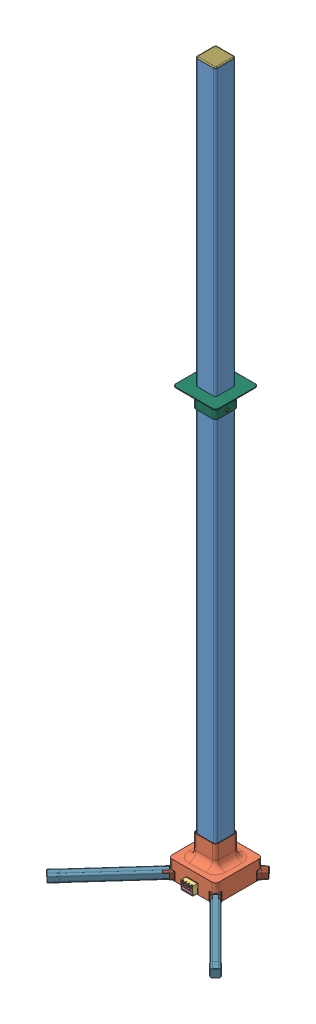
SolidWorks assembly GameOfLightLamp_V3, configuration Default. Lengths in mm.
Overall size (307.74 1257.8 307.74).
87 component instances, 35 part files, 55 mates.
Components (placement in the parent):
- Tube-1: Tube [Default] at origin size (35.56 1219.2 35.56)
- BottomCap^GameOfLightLamp_V3-1: BottomCap^GameOfLightLamp_V3 [Default] x (1 0 0) z (0 1 0) size (86.56 86.56 73.03) (virtual)
- MainBoard-1: MainBoard [Default] at (0 -14.3 0) size (70.02 38.08 102.19)
  - MainBoard-1: MainBoard [Default] at origin size (70.02 1.6 70.02)
  - 691311500104-1: 691311500104 [Default] at (1.7397 7.15 -0.127) x (0 0 1) z (0 1 0) size (22.32 8.5 16)
    - 691311500104_01-1: 691311500104_01 [Default] at origin size (1 1 15)
    - 691311500104_02-1: 691311500104_02 [Default] at origin size (1 1 15)
    - 691311500104_03-1: 691311500104_03 [Default] at origin size (1 1 15)
    - 691311500104_04-1: 691311500104_04 [Default] at origin size (1 1 15)
    - 691311500104_05-1: 691311500104_05 [Default] at origin size (22.32 8.5 12)
  - 691351500004-1: 691351500004 [Default] at (1.1147 18.3 -0.127) x (0 0 -1) z (-1 0 0) size (20.42 18.2 15.1)
    - 691351500004_01-1: 691351500004_01 [Default] at origin size (3.9 4.9 7)
    - 691351500004_02-1: 691351500004_02 [Default] at origin size (3.9 4.9 7)
    - 691351500004_03-1: 691351500004_03 [Default] at origin size (3.9 4.9 7)
    - 691351500004_04-1: 691351500004_04 [Default] at origin size (3.9 4.9 7)
    - 691351500004_05-1: 691351500004_05 [Default] at origin size (3.41 13.5 4.75)
    - 691351500004_06-1: 691351500004_06 [Default] at origin size (3.41 13.5 4.75)
    - 691351500004_07-1: 691351500004_07 [Default] at origin size (3.41 13.5 4.75)
    - 691351500004_08-1: 691351500004_08 [Default] at origin size (3.41 13.5 4.75)
    - 691351500004_09-1: 691351500004_09 [Default] at origin size (3.8 3.8 6.92)
    - 691351500004_10-1: 691351500004_10 [Default] at origin size (3.8 3.8 6.92)
    - 691351500004_11-1: 691351500004_11 [Default] at origin size (3.8 3.8 6.92)
    - 691351500004_12-1: 691351500004_12 [Default] at origin size (3.8 3.8 6.92)
    - 691351500004_13-1: 691351500004_13 [Default] at origin size (20.42 18.2 15.1)
    - 691351500004_14-1: 691351500004_14 [Default] at origin size (19.22 3 13.65)
  - 691351500004-2: 691351500004 [Default] at (-0.127 -4.675 -46.6672) x (1 0 0) z (0 -1 0) size (20.42 18.2 15.1)
    - 691351500004_01-1: 691351500004_01 [Default] at origin size (3.9 4.9 7)
    - 691351500004_02-1: 691351500004_02 [Default] at origin size (3.9 4.9 7)
    - 691351500004_03-1: 691351500004_03 [Default] at origin size (3.9 4.9 7)
    - 691351500004_04-1: 691351500004_04 [Default] at origin size (3.9 4.9 7)
    - 691351500004_05-1: 691351500004_05 [Default] at origin size (3.41 13.5 4.75)
    - 691351500004_06-1: 691351500004_06 [Default] at origin size (3.41 13.5 4.75)
    - 691351500004_07-1: 691351500004_07 [Default] at origin size (3.41 13.5 4.75)
    - 691351500004_08-1: 691351500004_08 [Default] at origin size (3.41 13.5 4.75)
    - 691351500004_09-1: 691351500004_09 [Default] at origin size (3.8 3.8 6.92)
    - 691351500004_10-1: 691351500004_10 [Default] at origin size (3.8 3.8 6.92)
    - 691351500004_11-1: 691351500004_11 [Default] at origin size (3.8 3.8 6.92)
    - 691351500004_12-1: 691351500004_12 [Default] at origin size (3.8 3.8 6.92)
    - 691351500004_13-1: 691351500004_13 [Default] at origin size (20.42 18.2 15.1)
    - 691351500004_14-1: 691351500004_14 [Default] at origin size (19.22 3 13.65)
  - 691351500004-3: 691351500004 [Default] at (0.1164 -4.675 46.6248) x (-1 0 0) z (0 -1 0) size (20.42 18.2 15.1)
    - 691351500004_01-1: 691351500004_01 [Default] at origin size (3.9 4.9 7)
    - 691351500004_02-1: 691351500004_02 [Default] at origin size (3.9 4.9 7)
    - 691351500004_03-1: 691351500004_03 [Default] at origin size (3.9 4.9 7)
    - 691351500004_04-1: 691351500004_04 [Default] at origin size (3.9 4.9 7)
    - 691351500004_05-1: 691351500004_05 [Default] at origin size (3.41 13.5 4.75)
    - 691351500004_06-1: 691351500004_06 [Default] at origin size (3.41 13.5 4.75)
    - 691351500004_07-1: 691351500004_07 [Default] at origin size (3.41 13.5 4.75)
    - 691351500004_08-1: 691351500004_08 [Default] at origin size (3.41 13.5 4.75)
    - 691351500004_09-1: 691351500004_09 [Default] at origin size (3.8 3.8 6.92)
    - 691351500004_10-1: 691351500004_10 [Default] at origin size (3.8 3.8 6.92)
    - 691351500004_11-1: 691351500004_11 [Default] at origin size (3.8 3.8 6.92)
    - 691351500004_12-1: 691351500004_12 [Default] at origin size (3.8 3.8 6.92)
    - 691351500004_13-1: 691351500004_13 [Default] at origin size (20.42 18.2 15.1)
    - 691351500004_14-1: 691351500004_14 [Default] at origin size (19.22 3 13.65)
  - 691312510004-1: 691312510004 [Default] at (0.1164 -4.05 35.4748) size (20.32 12 12)
    - 691312510004_01-1: 691312510004_01 [Default] at origin size (1 7.8 9.2)
    - 691312510004_02-1: 691312510004_02 [Default] at origin size (1 7.8 9.2)
    - 691312510004_03-1: 691312510004_03 [Default] at origin size (1 7.8 9.2)
    - 691312510004_04-1: 691312510004_04 [Default] at origin size (1 7.8 9.2)
    - 691312510004_05-1: 691312510004_05 [Default] at origin size (20.32 8.5 12)
  - 691312510004-2: 691312510004 [Default] at (-0.127 -4.05 -35.5172) x (-1 0 0) z (0 0 -1) size (20.32 12 12)
    - 691312510004_01-1: 691312510004_01 [Default] at origin size (1 7.8 9.2)
    - 691312510004_02-1: 691312510004_02 [Default] at origin size (1 7.8 9.2)
    - 691312510004_03-1: 691312510004_03 [Default] at origin size (1 7.8 9.2)
    - 691312510004_04-1: 691312510004_04 [Default] at origin size (1 7.8 9.2)
    - 691312510004_05-1: 691312510004_05 [Default] at origin size (20.32 8.5 12)
  - Part1^MainBoard-1: Part1^MainBoard [Default] at (-15.494 0 0) x (0 0 -1) z (1 0 0) size (8 8 10) (virtual)
- BottomLid^GameOfLightLamp_V3-1: BottomLid^GameOfLightLamp_V3 [Default] at (0 -14.3 0) x (-1 0 0) z (0 -1 0) size (103.15 103.15 17.42) (virtual)
- TopCap^GameOfLightLamp_V3-1: TopCap^GameOfLightLamp_V3 [Default] at (0 1219.2 0) x (1 0 0) z (0 1 0) size (39.28 39.28 21.05) (virtual)
- PVC^GameOfLightLamp_V3-1: PVC^GameOfLightLamp_V3 [Default] at (0 19.05 0) x (1 0 0) z (0 1 0) size (26.67 26.67 1200.15) (virtual)
- LampShade-1: LampShade [10in] at (0 919.2 0) size (254 100 254) (hidden)
- LampShade-2: LampShade [7in] at (0 1019.2 0) size (177.8 100 177.8) (hidden)
- LampShade-3: LampShade [7in] at (0 819.2 0) size (177.8 100 177.8) (hidden)
- LampShade-4: LampShade [4in] at (0 719.2 0) size (101.6 100 101.6) (hidden)
- LampShade-5: LampShade [4in] at (0 1119.2 0) size (101.6 100 101.6) (hidden)
- LegTube-1: LegTube [Default] at (40.5174 -23.9225 -40.5174) x (-0.707107 0 -0.707107) z (-0.025184 -0.999366 0.025184) size (14.48 152.91 14.48) (hidden)
- LegTube-5: LegTube [Default] at (40.5174 -23.9225 40.5174) x (0.707107 0 -0.707107) z (-0.025184 -0.999366 -0.025184) size (14.48 152.91 14.48)
- LegTube-6: LegTube [Default] at (-40.5174 -23.9225 40.5174) x (0.707107 0 0.707107) z (0.025184 -0.999366 -0.025184) size (14.48 152.91 14.48)
- LegTube-7: LegTube [Default] at (-40.5174 -23.9225 -40.5174) x (-0.707107 0 0.707107) z (0.025184 -0.999366 0.025184) size (14.48 152.91 14.48)
- HoldingCap^GameOfLightLamp_V3-1: HoldingCap^GameOfLightLamp_V3 [Default] at (0 719.2 0) x (-1 0 0) z (0 -1 0) size (76.03 76.03 33.75) (virtual)
- 94500A223_TYPE 316 SS BUTTON-HEAD SOCKET CAP SCREW-1: 94500A223_TYPE 316 SS BUTTON-HEAD SOCKET CAP SCREW [94500A223] at (21.53 691.8 0) x (0 0 -1) z (1 0 0) size (5.7 5.7 11.96)
- 94500A223_TYPE 316 SS BUTTON-HEAD SOCKET CAP SCREW-2: 94500A223_TYPE 316 SS BUTTON-HEAD SOCKET CAP SCREW [94500A223] at (-21.53 691.8 0) x (0 0 1) z (-1 0 0) size (5.7 5.7 11.96)
- 94500A223_TYPE 316 SS BUTTON-HEAD SOCKET CAP SCREW-7: 94500A223_TYPE 316 SS BUTTON-HEAD SOCKET CAP SCREW [94500A223] at (30.988 -17.95 30.988) x (0 0 1) z (0 -1 0) size (5.7 5.7 11.96)
- 94500A223_TYPE 316 SS BUTTON-HEAD SOCKET CAP SCREW-8: 94500A223_TYPE 316 SS BUTTON-HEAD SOCKET CAP SCREW [94500A223] at (-31.0092 -17.95 30.988) x (0 0 1) z (0 -1 0) size (5.7 5.7 11.96)
- 94500A223_TYPE 316 SS BUTTON-HEAD SOCKET CAP SCREW-9: 94500A223_TYPE 316 SS BUTTON-HEAD SOCKET CAP SCREW [94500A223] at (-31.0092 -17.95 -31.0092) x (0 0 1) z (0 -1 0) size (5.7 5.7 11.96)
- 94500A223_TYPE 316 SS BUTTON-HEAD SOCKET CAP SCREW-10: 94500A223_TYPE 316 SS BUTTON-HEAD SOCKET CAP SCREW [94500A223] at (30.988 -17.95 -31.0092) x (0 0 1) z (0 -1 0) size (5.7 5.7 11.96)
Mates (geometry in assembly coordinates):
- Coincident1: coordinate: point of Tube-1; point of assembly
- InPlace1: in place: plane of BottomCap^GameOfLightLamp_V3-1 through (0 0 0) normal (0 1 0); moOrthogonalPlaneRef_w of BottomCap^GameOfLightLamp_V3-1 through (0 0 0) normal (0 0 -1); line of BottomCap^GameOfLightLamp_V3-1 through (55 -55 0) axis (0 0 1); unknown of BottomCap^GameOfLightLamp_V3-1
- Coincident2: coincident aligned: plane of BottomCap^GameOfLightLamp_V3-1; plane of assembly
- Coincident3: coincident aligned: plane of BottomCap^GameOfLightLamp_V3-1 through (0 0 0) normal (0 0 -1); moOrthogonalPlaneRef_w of assembly
- Coincident4: coincident anti-aligned: plane of BottomCap^GameOfLightLamp_V3-1; moOrthogonalPlaneRef_w of assembly
- Coincident2: coincident: unknown of MainBoard-1/MainBoard-1
- Coincident3: coincident aligned: plane of MainBoard-1/MainBoard-1 through (0 -14.3 0) normal (0 0 1); plane of assembly through (0 0 0) normal (0 0 1)
- Coincident4: coincident aligned: plane of MainBoard-1/MainBoard-1 through (0 -14.3 0) normal (1 0 0); plane of assembly through (0 0 0) normal (1 0 0)
- Distance1: distance = 9.525 mm anti-aligned: plane of MainBoard-1/MainBoard-1 through (0 -12.7 0) normal (0 1 0); plane of BottomCap^GameOfLightLamp_V3-1 through (0 -3.175 0) normal (0 -1 0)
- InPlace2: in place: plane of BottomCap^GameOfLightLamp_V3-1 through (0 -47.8 0) normal (0 -1 0); plane of ? through (0 -47.8 0) normal (0 -1 0); plane of BottomCap^GameOfLightLamp_V3-1 through (0 -47.8 0) normal (0 -1 0); unknown of ?; plane of BottomCap^GameOfLightLamp_V3-1 through (0 -47.8 0) normal (0 -1 0); line of ? through (-55 0 -47.8) axis (0 -1 0); plane of BottomCap^GameOfLightLamp_V3-1 through (0 -14.3 0) normal (0 -1 0); unknown of BottomLid^GameOfLightLamp_V3-1
- Coincident5: coincident aligned: plane of BottomCap^GameOfLightLamp_V3-1; plane of BottomLid^GameOfLightLamp_V3-1
- Coincident6: coincident aligned: moOrthogonalPlaneRef_w of BottomCap^GameOfLightLamp_V3-1 through (0 -14.3 0) normal (0 0 -1); plane of BottomLid^GameOfLightLamp_V3-1
- Coincident7: coincident anti-aligned: moOrthogonalPlaneRef_w of BottomCap^GameOfLightLamp_V3-1 through (0 -14.3 0) normal (1 0 0); plane of BottomLid^GameOfLightLamp_V3-1
- InPlace3: in place: plane of Tube-1 through (-14.605 1219.2 14.605) normal (0 1 0); plane of TopCap^GameOfLightLamp_V3-1 through (0 1219.2 0) normal (0 1 0); plane of Tube-1 through (-14.605 1219.2 14.605) normal (0 1 0); plane of TopCap^GameOfLightLamp_V3-1 through (0 1219.2 0) normal (0 0 -1); plane of Tube-1 through (-14.605 1219.2 14.605) normal (0 1 0); line of TopCap^GameOfLightLamp_V3-1 through (-55 0 1219.2) axis (0 1 0); plane of Tube-1 through (-14.605 1219.2 14.605) normal (0 1 0); unknown of TopCap^GameOfLightLamp_V3-1
- Coincident8: coincident aligned: plane of Tube-1; plane of TopCap^GameOfLightLamp_V3-1
- Coincident9: coincident aligned: moOrthogonalPlaneRef_w of Tube-1 through (0 1219.2 0) normal (0 0 -1); plane of TopCap^GameOfLightLamp_V3-1 through (0 1219.2 0) normal (0 0 -1)
- Coincident10: coincident anti-aligned: moOrthogonalPlaneRef_w of Tube-1 through (0 1219.2 0) normal (-1 0 0); plane of TopCap^GameOfLightLamp_V3-1
- InPlace4: in place: plane of BottomCap^GameOfLightLamp_V3-1 through (0 3.175 0) normal (0 1 0); plane of ? through (0 3.175 0) normal (0 1 0); plane of BottomCap^GameOfLightLamp_V3-1 through (0 3.175 0) normal (0 1 0); plane of ? through (0 3.175 0) normal (0 0 -1); plane of BottomCap^GameOfLightLamp_V3-1 through (0 3.175 0) normal (0 1 0); line of ? through (-55 0 3.175) axis (0 1 0); plane of BottomCap^GameOfLightLamp_V3-1 through (0 19.05 0) normal (0 1 0); unknown of PVC^GameOfLightLamp_V3-1
- Coincident11: coincident aligned: plane of BottomCap^GameOfLightLamp_V3-1; plane of PVC^GameOfLightLamp_V3-1
- Coincident12: coincident aligned: moOrthogonalPlaneRef_w of BottomCap^GameOfLightLamp_V3-1 through (0 19.05 0) normal (0 0 -1); plane of PVC^GameOfLightLamp_V3-1 through (0 19.05 0) normal (0 0 -1)
- Coincident13: coincident anti-aligned: moOrthogonalPlaneRef_w of BottomCap^GameOfLightLamp_V3-1 through (0 19.05 0) normal (-1 0 0); plane of PVC^GameOfLightLamp_V3-1
- Coincident14: coincident aligned: plane of LampShade-5 through (19.05 1219.2 -19.05) normal (0 0 1); plane of LampShade-3 through (19.05 919.2 -19.05) normal (0 0 1)
- Coincident15: coincident aligned: plane of LampShade-5 through (19.05 1219.2 -19.05) normal (0 0 1); plane of LampShade-1 through (19.05 1019.2 -19.05) normal (0 0 1)
- Coincident16: coincident aligned: plane of LampShade-5 through (19.05 1219.2 -19.05) normal (0 0 1); plane of LampShade-2 through (19.05 1119.2 -19.05) normal (0 0 1)
- Coincident17: coincident aligned: plane of LampShade-5 through (19.05 1219.2 -19.05) normal (0 0 1); plane of LampShade-4 through (19.05 819.2 -19.05) normal (0 0 1)
- Coincident18: coincident aligned: plane of LampShade-5 through (-19.05 1219.2 19.05) normal (1 0 0); plane of LampShade-3 through (-19.05 919.2 19.05) normal (1 0 0)
- Coincident19: coincident aligned: plane of LampShade-5 through (-19.05 1219.2 19.05) normal (1 0 0); plane of LampShade-4 through (-19.05 819.2 19.05) normal (1 0 0)
- Coincident20: coincident aligned: plane of LampShade-5 through (-19.05 1219.2 19.05) normal (1 0 0); plane of LampShade-2 through (-19.05 1119.2 19.05) normal (1 0 0)
- Coincident21: coincident aligned: plane of LampShade-5 through (-19.05 1219.2 19.05) normal (1 0 0); plane of LampShade-1 through (-19.05 1019.2 19.05) normal (1 0 0)
- Coincident22: coincident anti-aligned: plane of LampShade-3 through (0 819.2 0) normal (0 -1 0); plane of LampShade-4 through (0 819.2 0) normal (0 1 0)
- Coincident23: coincident anti-aligned: plane of LampShade-1 through (0 919.2 0) normal (0 -1 0); plane of LampShade-3 through (0 919.2 0) normal (0 1 0)
- Coincident25: coincident anti-aligned: plane of LampShade-1 through (0 1019.2 0) normal (0 1 0); plane of LampShade-2 through (0 1019.2 0) normal (0 -1 0)
- Coincident26: coincident anti-aligned: plane of LampShade-2 through (0 1119.2 0) normal (0 1 0); plane of LampShade-5 through (0 1119.2 0) normal (0 -1 0)
- Width1: width anti-aligned: plane of Tube-1 through (-17.78 1219.2 14.605) normal (-1 0 0); plane of Tube-1 through (17.78 1219.2 14.605) normal (1 0 0); plane of LampShade-5 through (-19.05 1219.2 19.05) normal (1 0 0); plane of LampShade-5 through (19.05 1219.2 19.05) normal (-1 0 0)
- Width2: width aligned: plane of Tube-1 through (14.605 1219.2 17.78) normal (0 0 1); plane of Tube-1 through (14.605 1219.2 -17.78) normal (0 0 -1); plane of LampShade-5 through (19.05 1219.2 -19.05) normal (0 0 1); plane of LampShade-5 through (19.05 1219.2 19.05) normal (0 0 -1)
- Coincident27: coincident: line of TopCap^GameOfLightLamp_V3-1 through (-17.78 1219.2 -14.605) axis (0 0 1); plane of LampShade-5 through (0 1219.2 0) normal (0 1 0)
- InPlace5: in place: plane of LampShade-4 through (0 719.2 0) normal (0 -1 0); plane of HoldingCap^GameOfLightLamp_V3-1 through (0 719.2 0) normal (0 -1 0); plane of LampShade-4 through (0 719.2 0) normal (0 -1 0); unknown of HoldingCap^GameOfLightLamp_V3-1; plane of LampShade-4 through (0 719.2 0) normal (0 -1 0); line of HoldingCap^GameOfLightLamp_V3-1 through (-55 0 719.2) axis (0 -1 0); plane of LampShade-4 through (0 719.2 0) normal (0 -1 0); unknown of HoldingCap^GameOfLightLamp_V3-1
- Coincident31: coincident aligned: plane of LampShade-4; plane of HoldingCap^GameOfLightLamp_V3-1
- Coincident32: coincident aligned: moOrthogonalPlaneRef_w of LampShade-4 through (0 719.2 0) normal (0 0 -1); plane of HoldingCap^GameOfLightLamp_V3-1
- Coincident33: coincident anti-aligned: moOrthogonalPlaneRef_w of LampShade-4 through (0 719.2 0) normal (1 0 0); plane of HoldingCap^GameOfLightLamp_V3-1
- Concentric1: concentric anti-aligned: cylinder of HoldingCap^GameOfLightLamp_V3-1 through (38.0142 691.8 0) axis (-1 0 0) radius 1.25; cylinder of 94500A223_TYPE 316 SS BUTTON-HEAD SOCKET CAP SCREW-1 through (21.53 691.8 0) axis (1 0 0) radius 2.85
- Coincident34: coincident anti-aligned: plane of HoldingCap^GameOfLightLamp_V3-1 through (19.88 685.45 -14.605) normal (1 0 0); plane of 94500A223_TYPE 316 SS BUTTON-HEAD SOCKET CAP SCREW-1 through (19.88 688.95 0) normal (-1 0 0)
- Concentric2: concentric aligned: cylinder of HoldingCap^GameOfLightLamp_V3-1 through (38.0142 691.8 0) axis (-1 0 0) radius 1.25; cylinder of 94500A223_TYPE 316 SS BUTTON-HEAD SOCKET CAP SCREW-2 through (-21.53 691.8 0) axis (-1 0 0) radius 2.85
- Coincident35: coincident anti-aligned: plane of HoldingCap^GameOfLightLamp_V3-1 through (-19.88 685.45 14.605) normal (-1 0 0); plane of 94500A223_TYPE 316 SS BUTTON-HEAD SOCKET CAP SCREW-2 through (-19.88 688.95 0) normal (1 0 0)
- Concentric7: concentric aligned: cylinder of MainBoard-1/MainBoard-1 through (30.988 -12.7 30.988) axis (0 -1 0) radius 1.5; cylinder of 94500A223_TYPE 316 SS BUTTON-HEAD SOCKET CAP SCREW-7 through (30.988 -17.95 30.988) axis (0 -1 0) radius 2.85
- Concentric8: concentric aligned: cylinder of MainBoard-1/MainBoard-1 through (30.988 -12.7 -31.0092) axis (0 -1 0) radius 1.5; cylinder of 94500A223_TYPE 316 SS BUTTON-HEAD SOCKET CAP SCREW-10 through (30.988 -17.95 -31.0092) axis (0 -1 0) radius 2.85
- Concentric9: concentric aligned: cylinder of MainBoard-1/MainBoard-1 through (-31.0092 -12.7 30.988) axis (0 -1 0) radius 1.5; cylinder of 94500A223_TYPE 316 SS BUTTON-HEAD SOCKET CAP SCREW-8 through (-31.0092 -17.95 30.988) axis (0 -1 0) radius 2.85
- Concentric10: concentric aligned: cylinder of MainBoard-1/MainBoard-1 through (-31.0092 -12.7 -31.0092) axis (0 -1 0) radius 1.5; cylinder of 94500A223_TYPE 316 SS BUTTON-HEAD SOCKET CAP SCREW-9 through (-31.0092 -17.95 -31.0092) axis (0 -1 0) radius 2.85
- Coincident40: coincident anti-aligned: plane of BottomLid^GameOfLightLamp_V3-1 through (-22.1467 -16.3 -36.3422) normal (0 -1 0); plane of 94500A223_TYPE 316 SS BUTTON-HEAD SOCKET CAP SCREW-8 through (-28.1592 -16.3 30.988) normal (0 1 0)
- Coincident41: coincident anti-aligned: plane of BottomLid^GameOfLightLamp_V3-1 through (-22.1467 -16.3 -36.3422) normal (0 -1 0); plane of 94500A223_TYPE 316 SS BUTTON-HEAD SOCKET CAP SCREW-7 through (33.838 -16.3 30.988) normal (0 1 0)
- Coincident42: coincident anti-aligned: plane of BottomLid^GameOfLightLamp_V3-1 through (-22.1467 -16.3 -36.3422) normal (0 -1 0); plane of 94500A223_TYPE 316 SS BUTTON-HEAD SOCKET CAP SCREW-10 through (33.838 -16.3 -31.0092) normal (0 1 0)
- Coincident43: coincident anti-aligned: plane of BottomLid^GameOfLightLamp_V3-1 through (-22.1467 -16.3 -36.3422) normal (0 -1 0); plane of 94500A223_TYPE 316 SS BUTTON-HEAD SOCKET CAP SCREW-9 through (-28.1592 -16.3 -31.0092) normal (0 1 0)
- Coincident45: coincident anti-aligned: plane of BottomLid^GameOfLightLamp_V3-1 through (43.4619 -28.2378 -37.3554) normal (0.706658 -0.035616 -0.706658); plane of LegTube-1 through (43.1155 -27.7301 -37.7274) normal (-0.706658 0.035616 0.706658)
- Width3: width aligned: plane of LegTube-1 through (152.8757 -33.1579 -143.3566) normal (-0.707107 0 -0.707107); plane of LegTube-1 through (143.3566 -33.1579 -152.8757) normal (0.707107 0 0.707107); plane of BottomLid^GameOfLightLamp_V3-1 through (45.5473 -19.6073 -35.705) normal (0.707107 0 0.707107); plane of BottomLid^GameOfLightLamp_V3-1 through (35.4875 -28.2378 -45.3298) normal (-0.707107 0 -0.707107)
- Width4: width aligned: plane of BottomLid^GameOfLightLamp_V3-1 through (37.6394 -16.9673 -43.7459) normal (0.025184 0.999366 -0.025184); plane of BottomLid^GameOfLightLamp_V3-1 through (43.3954 -30.8777 -37.2888) normal (-0.025184 -0.999366 0.025184); plane of LegTube-1 through (145.6875 -22.6236 -151.0757) normal (-0.025184 -0.999366 0.025184); plane of LegTube-1 through (145.3485 -36.0771 -150.7367) normal (0.025184 0.999366 -0.025184)
